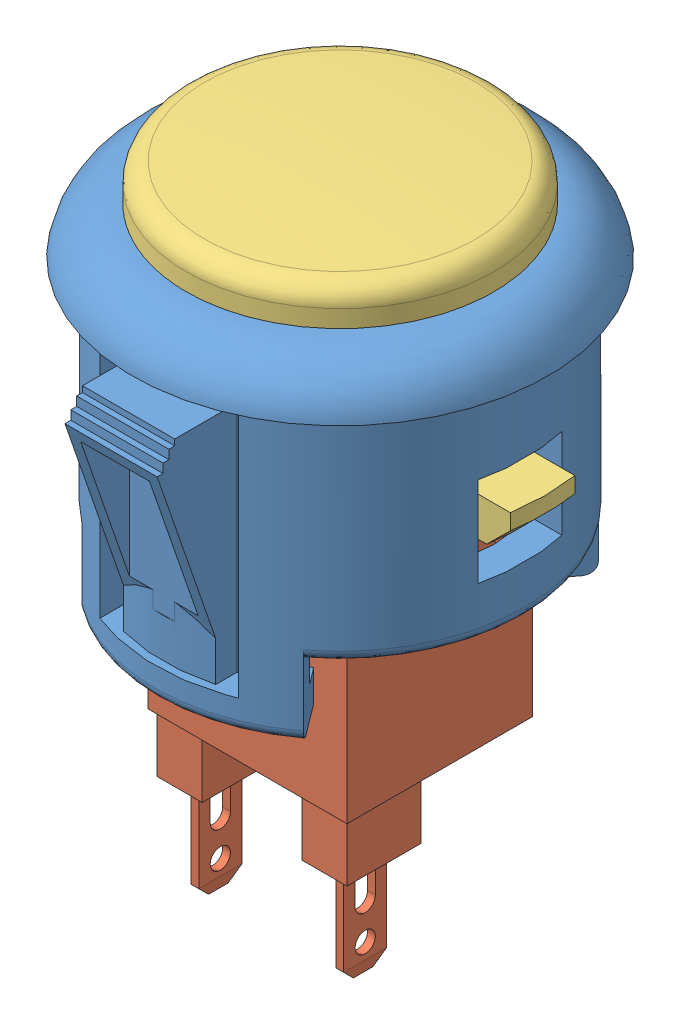
SolidWorks assembly !sanwa_button, configuration Default. Lengths in mm.
Overall size (27 41.99 29.8).
3 component instances, 3 part files, 4 mates.
Components (placement in the parent):
- base-1: base [Default] at (-11.8549 15.7525 1.5934) size (27 22.1 29.8)
- microswitch-1: microswitch [Default] at (-11.8549 -9.9495 1.5934) x (1 0 0) z (0 1 0) size (15.01 12.07 29.85)
- top_cap-1: top_cap [Default] at (-11.8549 15.4558 1.5934) size (26.67 15.14 20)
Mates (geometry in assembly coordinates):
- Coincident1: coincident aligned: plane of microswitch-1 through (-11.8549 1.2265 16.7147) normal (0 -1 0); plane of base-1 through (-3.1554 1.2265 1.5934) normal (0 -1 0)
- Concentric1: concentric anti-aligned: cylinder of base-1 through (-11.8549 18.7525 1.5934) axis (0 1 0) radius 10; cylinder of top_cap-1 through (-11.8549 15.4558 1.5934) axis (0 -1 0) radius 10
- Parallel1: parallel aligned: plane of microswitch-1 through (-12.6169 9.3545 4.6033) normal (-1 0 0); plane of top_cap-1 through (-10.9659 25.8399 -1.4927) normal (-1 0 0)
- LimitDistance1: limit distance = 3.6068 mm anti-aligned: plane of top_cap-1 through (-11.8549 6.3573 1.5934) normal (0 -1 0); plane of microswitch-1 through (-18.3319 2.7505 7.6259) normal (0 1 0)
